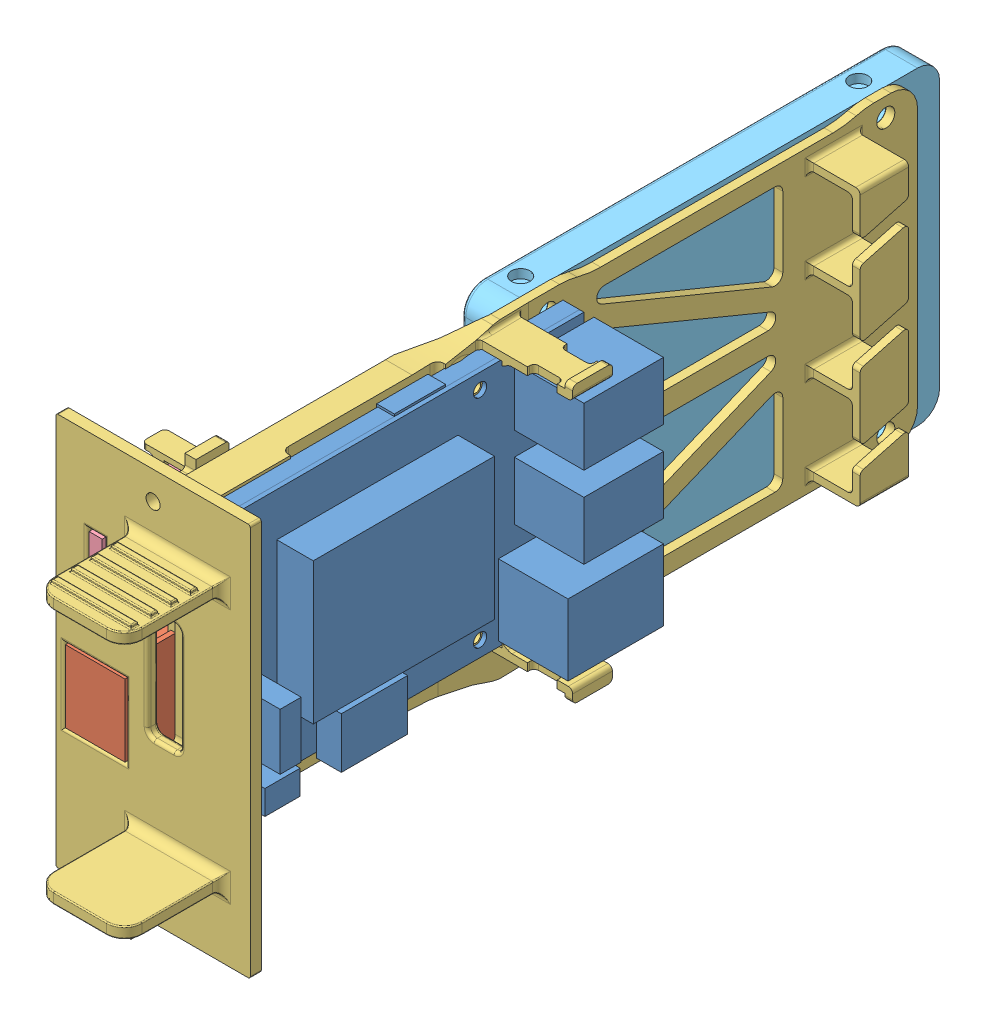
SolidWorks assembly Assem1, configuration Default. Lengths in mm.
Overall size (44 88.9 201.5).
5 component instances, 5 part files, 15 mates.
Components (placement in the parent):
- ODroid_C2.2-1: ODroid_C2.2 [Default] at (4.5 4 -49.5) x (0 0 1) z (1 0 0) size (87.25 57.65 20.75)
- POE-1: POE [Default] at (-5.25 -8 -39.305) x (0 0 -1) z (-1 0 0) size (74.68 25.1 17.85)
- Rack_base-2: Rack_base [Default] x (-1 0 0) z (0 0 -1) size (44 88.9 194.5)
- ODroid-UART-1: ODroid-UART [Default] at (-11.5 21 -1) x (0 0 -1) z (0 1 0) size (27.4 6.3 13.57)
- SSD-1: SSD [Default] at (-1.5 0 -79.5) x (0 0 -1) z (-1 0 0) size (100 70.15 8.25)
Mates (geometry in assembly coordinates):
- Coincident12: coincident anti-aligned: plane of Rack_base-2 through (0 0 0) normal (-1 0 0); plane of assembly through (0 0 0) normal (1 0 0)
- Distance7: distance = 0 mm aligned: plane of Rack_base-2; plane of assembly through (0 0 0) normal (0 1 0)
- Coincident3: coincident anti-aligned: plane of Rack_base-2 through (0 0 0) normal (0 0 -1); plane of assembly through (0 0 0) normal (0 0 1)
- Distance1: distance = 7 mm anti-aligned: plane of Rack_base-2 through (0 0 0) normal (0 0 -1); plane of ODroid_C2.2-1 through (0.75 -23.975 -7) normal (0 0 1)
- Distance6: distance = 4.5 mm anti-aligned: plane of ODroid_C2.2-1 through (4.5 4 -49.5) normal (1 0 0); plane of Rack_base-2 through (0 0 0) normal (-1 0 0)
- Distance16: distance = 4 mm anti-aligned: plane of ODroid_C2.2-1; plane of Rack_base-2
- Distance3: distance = 9.75 mm anti-aligned: plane of POE-1 through (-5.25 -8 -39.305) normal (-1 0 0); plane of ODroid_C2.2-1 through (4.5 4 -49.5) normal (1 0 0)
- Coincident17: coincident aligned: plane of POE-1 through (-19.85 -16.15 0) normal (0 0 1); plane of Rack_base-2 through (0 0 0) normal (0 0 1)
- Distance10: distance = 17 mm anti-aligned: plane of ODroid_C2.2-1; plane of ODroid-UART-1 through (-11.5 21 -1) normal (0 1 0)
- Distance8: distance = 1 mm anti-aligned: plane of ODroid-UART-1; plane of Rack_base-2 through (0 0 0) normal (0 0 1)
- Distance11: distance = 16 mm anti-aligned: plane of ODroid-UART-1; plane of ODroid_C2.2-1 through (4.5 4 -49.5) normal (1 0 0)
- Distance12: distance = 12 mm aligned: plane of POE-1; plane of ODroid_C2.2-1
- Distance14: distance = 6 mm anti-aligned: plane of ODroid_C2.2-1 through (4.5 4 -49.5) normal (1 0 0); plane of SSD-1 through (-1.5 0 -79.5) normal (-1 0 0)
- Distance13: distance = 30 mm anti-aligned: plane of ODroid_C2.2-1; plane of SSD-1
- Distance17: distance = 0 mm anti-aligned: plane of Rack_base-2; plane of SSD-1
